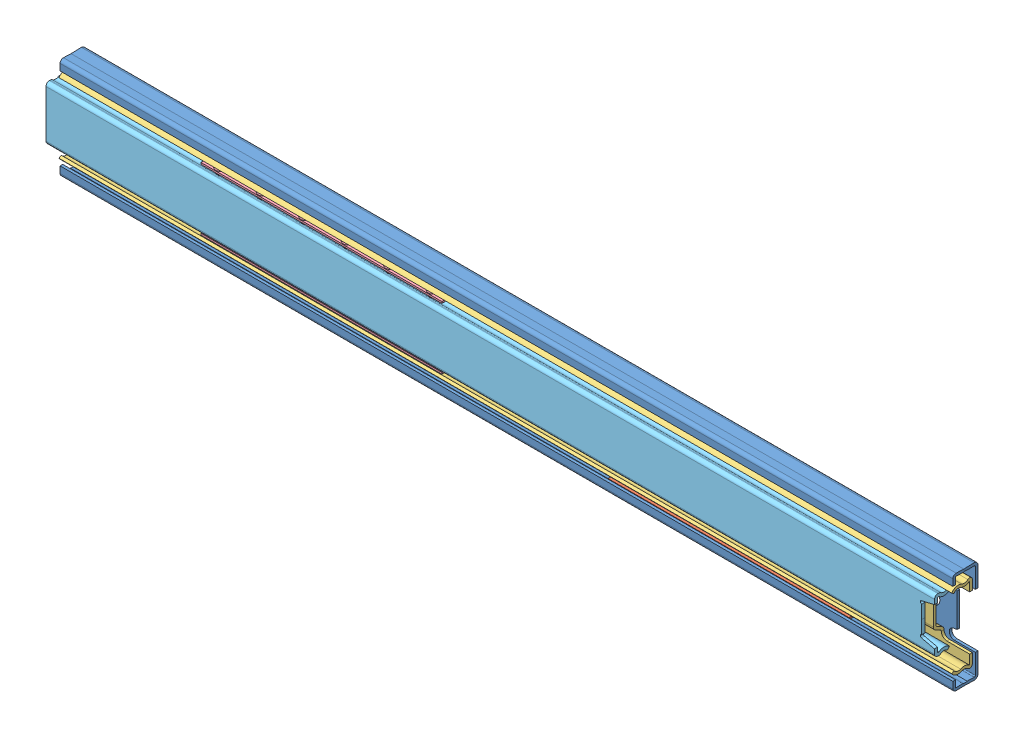
SolidWorks assembly Slide Riel, configuration Predeterminado. Lengths in mm.
Overall size (404.99 45.64 12.66).
7 component instances, 5 part files, 18 mates.
Components (placement in the parent):
- base suport slide-1: base suport slide [Open] at (185.9481 -32.6274 -0.7112) size (400.05 45.64 11.28)
- ball bearing base suport slide-1: ball bearing base suport slide [Open] at (423.4399 -32.6026 -1.2218) x (1 0 0) z (0 -0.026177 0.999657) size (107.95 5.02 7.62)
- ball bearing base suport slide-2: ball bearing base suport slide [Open] at (423.4399 -70.9883 -0.2379) x (1 0 0) z (0 0.026177 0.999657) size (107.95 5.02 7.62)
- medium suport slide-1: medium suport slide [Open] at (388.7185 -32.6274 -0.7256) size (400.05 35.19 9.27)
- ball bearing medium suport slide-1: ball bearing medium suport slide [Open] at (420.131 -60.0935 -0.7456) size (107.95 4.6 5.08)
- ball bearing medium suport slide-2: ball bearing medium suport slide [Open] at (420.131 -32.6515 -0.7456) size (107.95 4.6 5.08)
- final suport slide-1: final suport slide [Open] at (585.5018 -32.6274 -0.7552) size (398.14 24.29 6.76)
Mates (geometry in assembly coordinates):
- Distancia1: distance = 1.95 mm anti-aligned: plane of ball bearing base suport slide-1 through (229.7649 -13.1576 3.2511) normal (0 0.999657 0.026177); plane of base suport slide-1 through (385.9731 -11.0005 -4.6349) normal (0 -0.999657 -0.026177)
- Distancia3: distance = 0.77 mm: line of ball bearing base suport slide-1 through (229.7649 -13.7199 -4.3862) axis (1 0 0); plane of base suport slide-1 through (385.9731 -11.5083 -5.1562) normal (0 0 1)
- Distancia4: distance = 1.95 mm anti-aligned: plane of ball bearing base suport slide-2 through (229.7649 -52.0976 3.2312) normal (0 -0.999657 0.026177); plane of base suport slide-1 through (385.9731 -54.2543 -4.6349) normal (0 0.999657 -0.026177)
- Distancia5: distance = 0.77 mm: line of ball bearing base suport slide-2 through (229.7649 -52.2971 -4.3862) axis (1 0 0); plane of base suport slide-1 through (385.9731 -11.5083 -5.1562) normal (0 0 1)
- Coincidente2: coincident aligned: plane of ball bearing base suport slide-1; plane of ball bearing base suport slide-2
- Distancia límite1: limit distance = 243.8418 mm aligned: plane of base suport slide-1 through (-14.0769 -11.5083 -4.6482) normal (-1 0 0); plane of ball bearing base suport slide-2 through (229.7649 -51.3359 3.2112) normal (-1 0 0)
- Distancia7: distance = 0.9 mm anti-aligned: plane of medium suport slide-1 through (385.5435 -16.2508 -4.2562) normal (0 0 -1); plane of base suport slide-1 through (385.9731 -11.5083 -5.1562) normal (0 0 1)
- Coincidente5: coincident aligned: plane of base suport slide-1 through (185.9481 -32.6274 -0.7112) normal (0 1 0); plane of medium suport slide-1 through (388.7185 -32.6274 -0.7256) normal (0 1 0)
- Distancia límite2: limit distance = 244.2714 mm aligned: plane of ball bearing base suport slide-1 through (229.7649 -13.1576 3.2511) normal (-1 0 0); plane of medium suport slide-1 through (-14.5065 -26.5114 -1.4622) normal (-1 0 0)
- Distancia10: distance = 2.52 mm anti-aligned: plane of ball bearing medium suport slide-1 through (48.656 -45.9674 -0.517) normal (0 0 -1); plane of medium suport slide-1 through (385.5435 -49.0039 -3.037) normal (0 0 1)
- Distancia11: distance = 13.34 mm aligned: plane of ball bearing medium suport slide-1 through (48.656 -45.9674 -0.517) normal (0 1 0); plane of base suport slide-1 through (185.9481 -32.6274 -0.7112) normal (0 1 0)
- Distancia12: distance = 2.52 mm anti-aligned: plane of medium suport slide-1 through (385.5435 -16.2508 -3.037) normal (0 0 1); plane of ball bearing medium suport slide-2 through (48.656 -18.5254 -0.517) normal (0 0 -1)
- Distancia13: distance = 13.34 mm anti-aligned: plane of ball bearing medium suport slide-2 through (48.656 -19.2874 -0.517) normal (0 -1 0); plane of base suport slide-1 through (185.9481 -32.6274 -0.7112) normal (0 1 0)
- Coincidente12: coincident aligned: plane of ball bearing medium suport slide-1 through (420.131 -60.0935 -0.7456) normal (1 0 0); plane of ball bearing medium suport slide-2 through (420.131 -32.6515 -0.7456) normal (1 0 0)
- Distancia límite3: limit distance = 63.1624 mm aligned: plane of ball bearing medium suport slide-1 through (48.656 -46.7294 -0.517) normal (-1 0 0); plane of medium suport slide-1 through (-14.5065 -26.5114 -1.4622) normal (-1 0 0)
- Coincidente13: coincident aligned: plane of base suport slide-1 through (185.9481 -32.6274 -0.7112) normal (0 1 0); plane of final suport slide-1 through (585.5018 -32.6274 -0.7552) normal (0 1 0)
- Distancia15: distance = 4.39 mm anti-aligned: plane of final suport slide-1 through (379.1268 -32.6274 4.909) normal (0 0 -1); plane of medium suport slide-1 through (385.5435 -26.5114 0.519) normal (0 0 1)
- Distancia límite4: limit distance = 67.6742 mm aligned: plane of ball bearing medium suport slide-2 through (48.656 -19.2874 -0.517) normal (-1 0 0); plane of final suport slide-1 through (-19.0182 -32.6274 -6.394) normal (-1 0 0)
